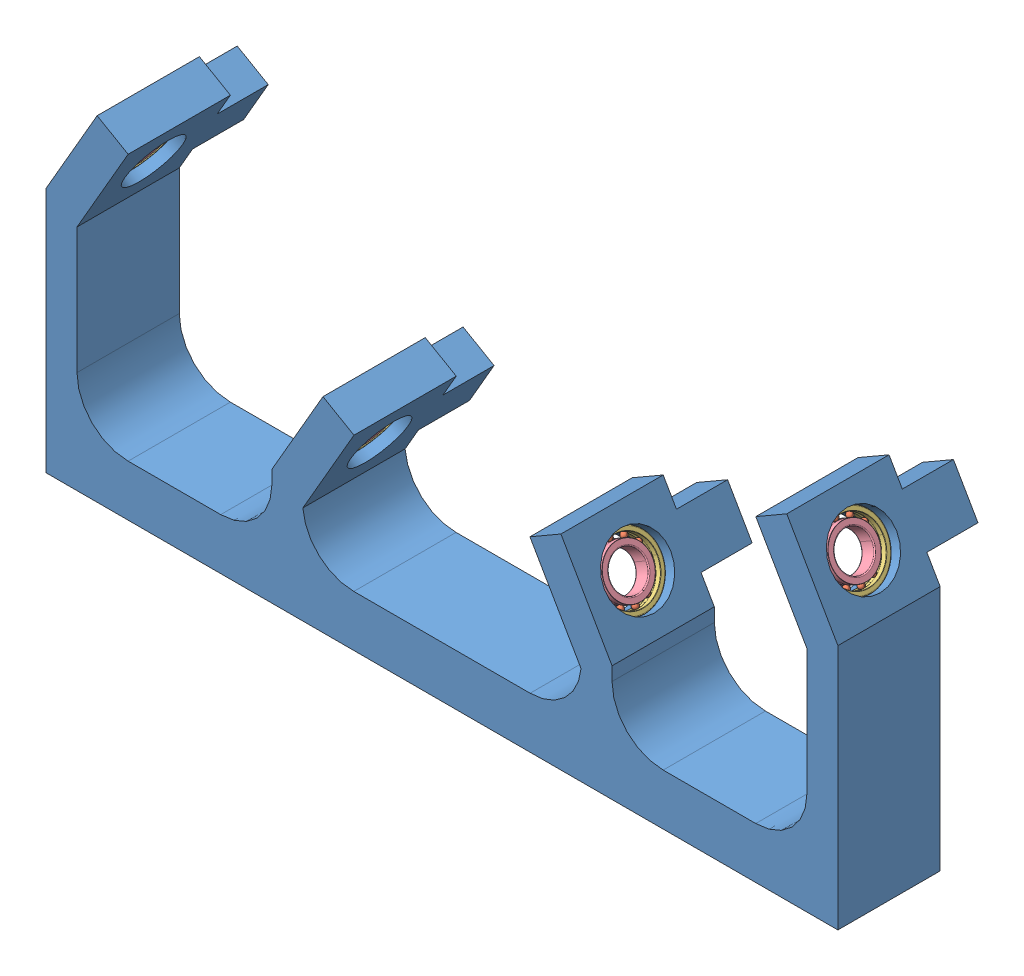
SolidWorks assembly support rouleau, configuration Défaut. Lengths in mm.
Overall size (154.87 65.48 30).
61 component instances, 4 part files, 8 mates.
Components (placement in the parent):
- support rouleau2-1: support rouleau2 [Défaut] at (-2.3977 -25.7602 154.8705) size (154.87 65.48 30)
- SKF_W_627_X-1: SKF_W_627_X [Default] at (-73.1009 15.0603 154.8705) x (0.866025 -0.5 0) z (0 0 1) size (3 13 13)
  - SKF_W_627_X_16-1: SKF_W_627_X_16 [Default] x (1 0 0) z (0 -0.5 0.866025) size (1.2 1.2 1.2)
  - SKF_W_627_X_16-2: SKF_W_627_X_16 [Default] x (1 0 0) z (0 -0.866025 0.5) size (1.2 1.2 1.2)
  - SKF_W_627_X_16-3: SKF_W_627_X_16 [Default] x (1 0 0) z (0 -1 0) size (1.2 1.2 1.2)
  - SKF_W_627_X_16-4: SKF_W_627_X_16 [Default] x (1 0 0) z (0 -0.866025 -0.5) size (1.2 1.2 1.2)
  - SKF_W_627_X_16-5: SKF_W_627_X_16 [Default] x (1 0 0) z (0 -0.5 -0.866025) size (1.2 1.2 1.2)
  - SKF_W_627_X_16-6: SKF_W_627_X_16 [Default] x (1 0 0) z (0 0 -1) size (1.2 1.2 1.2)
  - SKF_W_627_X_16-7: SKF_W_627_X_16 [Default] x (1 0 0) z (0 0.5 -0.866025) size (1.2 1.2 1.2)
  - SKF_W_627_X_16-8: SKF_W_627_X_16 [Default] x (1 0 0) z (0 0.866025 -0.5) size (1.2 1.2 1.2)
  - SKF_W_627_X_16-9: SKF_W_627_X_16 [Default] x (1 0 0) z (0 1 0) size (1.2 1.2 1.2)
  - SKF_W_627_X_16-10: SKF_W_627_X_16 [Default] x (1 0 0) z (0 0.866025 0.5) size (1.2 1.2 1.2)
  - SKF_W_627_X_16-11: SKF_W_627_X_16 [Default] x (1 0 0) z (0 0.5 0.866025) size (1.2 1.2 1.2)
  - SKF_W_627_X_16-12: SKF_W_627_X_16 [Default] at origin size (1.2 1.2 1.2)
  - SKF_W_627_X_29-1: SKF_W_627_X_29 [Default] at origin size (3 13 13)
  - SKF_W_627_X_31-1: SKF_W_627_X_31 [Default] at origin size (3 9.35 9.35)
- SKF_W_627_X-2: SKF_W_627_X [Default] at (21.5401 -11.9397 154.8705) x (0.866025 0.5 0) z (0 0 1) size (3 13 13)
  - SKF_W_627_X_16-1: SKF_W_627_X_16 [Default] x (1 0 0) z (0 -0.5 0.866025) size (1.2 1.2 1.2)
  - SKF_W_627_X_16-2: SKF_W_627_X_16 [Default] x (1 0 0) z (0 -0.866025 0.5) size (1.2 1.2 1.2)
  - SKF_W_627_X_16-3: SKF_W_627_X_16 [Default] x (1 0 0) z (0 -1 0) size (1.2 1.2 1.2)
  - SKF_W_627_X_16-4: SKF_W_627_X_16 [Default] x (1 0 0) z (0 -0.866025 -0.5) size (1.2 1.2 1.2)
  - SKF_W_627_X_16-5: SKF_W_627_X_16 [Default] x (1 0 0) z (0 -0.5 -0.866025) size (1.2 1.2 1.2)
  - SKF_W_627_X_16-6: SKF_W_627_X_16 [Default] x (1 0 0) z (0 0 -1) size (1.2 1.2 1.2)
  - SKF_W_627_X_16-7: SKF_W_627_X_16 [Default] x (1 0 0) z (0 0.5 -0.866025) size (1.2 1.2 1.2)
  - SKF_W_627_X_16-8: SKF_W_627_X_16 [Default] x (1 0 0) z (0 0.866025 -0.5) size (1.2 1.2 1.2)
  - SKF_W_627_X_16-9: SKF_W_627_X_16 [Default] x (1 0 0) z (0 1 0) size (1.2 1.2 1.2)
  - SKF_W_627_X_16-10: SKF_W_627_X_16 [Default] x (1 0 0) z (0 0.866025 0.5) size (1.2 1.2 1.2)
  - SKF_W_627_X_16-11: SKF_W_627_X_16 [Default] x (1 0 0) z (0 0.5 0.866025) size (1.2 1.2 1.2)
  - SKF_W_627_X_16-12: SKF_W_627_X_16 [Default] at origin size (1.2 1.2 1.2)
  - SKF_W_627_X_29-1: SKF_W_627_X_29 [Default] at origin size (3 13 13)
  - SKF_W_627_X_31-1: SKF_W_627_X_31 [Default] at origin size (3 9.35 9.35)
- SKF_W_627_X-3: SKF_W_627_X [Default] at (-28.9336 -10.4397 154.8705) x (0.866025 -0.5 0) z (0 0 1) size (3 13 13)
  - SKF_W_627_X_16-1: SKF_W_627_X_16 [Default] x (1 0 0) z (0 -0.5 0.866025) size (1.2 1.2 1.2)
  - SKF_W_627_X_16-2: SKF_W_627_X_16 [Default] x (1 0 0) z (0 -0.866025 0.5) size (1.2 1.2 1.2)
  - SKF_W_627_X_16-3: SKF_W_627_X_16 [Default] x (1 0 0) z (0 -1 0) size (1.2 1.2 1.2)
  - SKF_W_627_X_16-4: SKF_W_627_X_16 [Default] x (1 0 0) z (0 -0.866025 -0.5) size (1.2 1.2 1.2)
  - SKF_W_627_X_16-5: SKF_W_627_X_16 [Default] x (1 0 0) z (0 -0.5 -0.866025) size (1.2 1.2 1.2)
  - SKF_W_627_X_16-6: SKF_W_627_X_16 [Default] x (1 0 0) z (0 0 -1) size (1.2 1.2 1.2)
  - SKF_W_627_X_16-7: SKF_W_627_X_16 [Default] x (1 0 0) z (0 0.5 -0.866025) size (1.2 1.2 1.2)
  - SKF_W_627_X_16-8: SKF_W_627_X_16 [Default] x (1 0 0) z (0 0.866025 -0.5) size (1.2 1.2 1.2)
  - SKF_W_627_X_16-9: SKF_W_627_X_16 [Default] x (1 0 0) z (0 1 0) size (1.2 1.2 1.2)
  - SKF_W_627_X_16-10: SKF_W_627_X_16 [Default] x (1 0 0) z (0 0.866025 0.5) size (1.2 1.2 1.2)
  - SKF_W_627_X_16-11: SKF_W_627_X_16 [Default] x (1 0 0) z (0 0.5 0.866025) size (1.2 1.2 1.2)
  - SKF_W_627_X_16-12: SKF_W_627_X_16 [Default] at origin size (1.2 1.2 1.2)
  - SKF_W_627_X_29-1: SKF_W_627_X_29 [Default] at origin size (3 13 13)
  - SKF_W_627_X_31-1: SKF_W_627_X_31 [Default] at origin size (3 9.35 9.35)
- SKF_W_627_X-4: SKF_W_627_X [Default] at (65.7074 13.5603 154.8705) x (0.866025 0.5 0) z (0 0 1) size (3 13 13)
  - SKF_W_627_X_16-1: SKF_W_627_X_16 [Default] x (1 0 0) z (0 -0.5 0.866025) size (1.2 1.2 1.2)
  - SKF_W_627_X_16-2: SKF_W_627_X_16 [Default] x (1 0 0) z (0 -0.866025 0.5) size (1.2 1.2 1.2)
  - SKF_W_627_X_16-3: SKF_W_627_X_16 [Default] x (1 0 0) z (0 -1 0) size (1.2 1.2 1.2)
  - SKF_W_627_X_16-4: SKF_W_627_X_16 [Default] x (1 0 0) z (0 -0.866025 -0.5) size (1.2 1.2 1.2)
  - SKF_W_627_X_16-5: SKF_W_627_X_16 [Default] x (1 0 0) z (0 -0.5 -0.866025) size (1.2 1.2 1.2)
  - SKF_W_627_X_16-6: SKF_W_627_X_16 [Default] x (1 0 0) z (0 0 -1) size (1.2 1.2 1.2)
  - SKF_W_627_X_16-7: SKF_W_627_X_16 [Default] x (1 0 0) z (0 0.5 -0.866025) size (1.2 1.2 1.2)
  - SKF_W_627_X_16-8: SKF_W_627_X_16 [Default] x (1 0 0) z (0 0.866025 -0.5) size (1.2 1.2 1.2)
  - SKF_W_627_X_16-9: SKF_W_627_X_16 [Default] x (1 0 0) z (0 1 0) size (1.2 1.2 1.2)
  - SKF_W_627_X_16-10: SKF_W_627_X_16 [Default] x (1 0 0) z (0 0.866025 0.5) size (1.2 1.2 1.2)
  - SKF_W_627_X_16-11: SKF_W_627_X_16 [Default] x (1 0 0) z (0 0.5 0.866025) size (1.2 1.2 1.2)
  - SKF_W_627_X_16-12: SKF_W_627_X_16 [Default] at origin size (1.2 1.2 1.2)
  - SKF_W_627_X_29-1: SKF_W_627_X_29 [Default] at origin size (3 13 13)
  - SKF_W_627_X_31-1: SKF_W_627_X_31 [Default] at origin size (3 9.35 9.35)
Mates (geometry in assembly coordinates):
- Coaxiale1: concentric anti-aligned: cylinder of support rouleau-1 through (-20.2733 -15.4397 154.8705) axis (-0.866025 0.5 0) radius 6.5; cylinder of SKF_W_627_X-1/SKF_W_627_X_29-1 through (-70.5028 13.5603 154.8705) axis (0.866025 -0.5 0) radius 6.5
- Coïncidente1: coincident anti-aligned: circle of support rouleau-1; plane of SKF_W_627_X-1/SKF_W_627_X_29-1 through (-67.682 18.4461 154.8705) normal (0.866025 -0.5 0)
- Coaxiale2: concentric anti-aligned: cylinder of support rouleau-1 through (-20.2733 -15.4397 154.8705) axis (-0.866025 0.5 0) radius 6.5; cylinder of SKF_W_627_X-3/SKF_W_627_X_29-1 through (-26.3355 -11.9397 154.8705) axis (0.866025 -0.5 0) radius 6.5
- Coïncidente2: coincident anti-aligned: plane of support rouleau-1 through (-26.3355 -11.9397 154.8705) normal (-0.866025 0.5 0); plane of SKF_W_627_X-3/SKF_W_627_X_29-1 through (-23.5147 -7.0539 154.8705) normal (0.866025 -0.5 0)
- Coaxiale3: concentric aligned: cylinder of support rouleau-1 through (15.478 -15.4397 154.8705) axis (0.866025 0.5 0) radius 6.5; cylinder of SKF_W_627_X-2/SKF_W_627_X_29-1 through (24.1382 -10.4397 154.8705) axis (0.866025 0.5 0) radius 6.5
- Coïncidente3: coincident anti-aligned: plane of support rouleau-1 through (21.5401 -11.9397 154.8705) normal (0.866025 0.5 0); plane of SKF_W_627_X-2/SKF_W_627_X_29-1 through (18.3901 -6.4838 154.8705) normal (-0.866025 -0.5 0)
- Coaxiale4: concentric aligned: cylinder of support rouleau-1 through (15.478 -15.4397 154.8705) axis (0.866025 0.5 0) radius 6.5; cylinder of SKF_W_627_X-4/SKF_W_627_X_29-1 through (68.3055 15.0603 154.8705) axis (0.866025 0.5 0) radius 6.5
- Coïncidente4: coincident anti-aligned: plane of support rouleau-1 through (65.7074 13.5603 154.8705) normal (0.866025 0.5 0); plane of SKF_W_627_X-4/SKF_W_627_X_29-1 through (62.5574 19.0162 154.8705) normal (-0.866025 -0.5 0)
